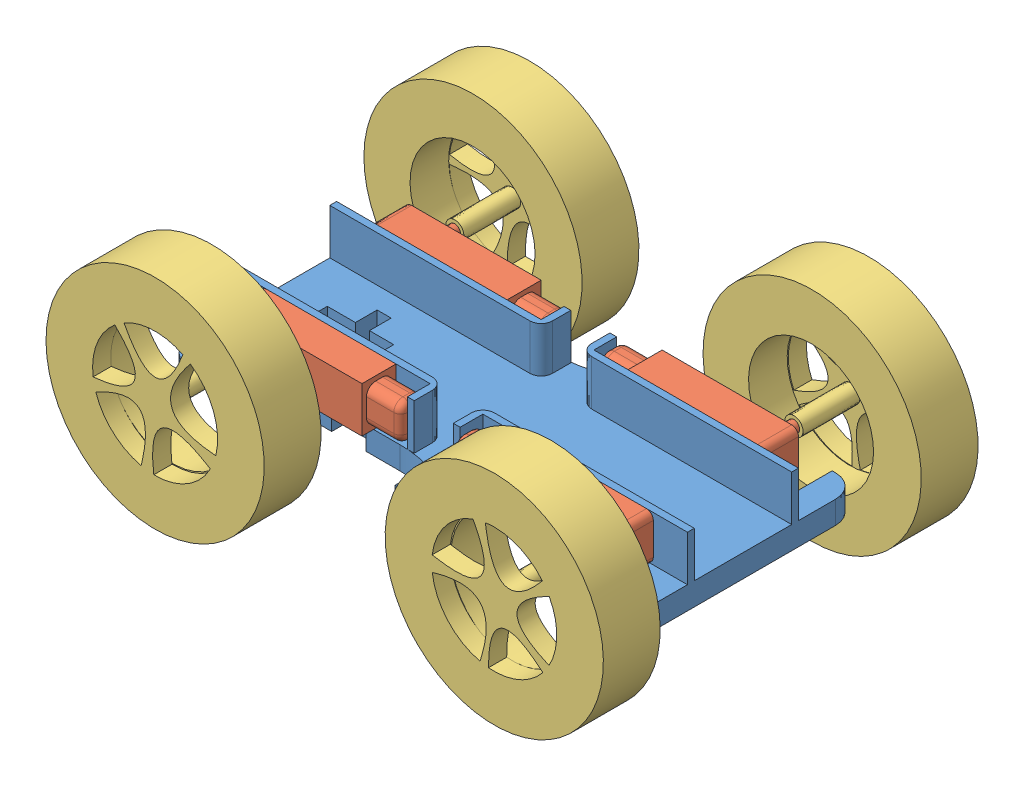
SolidWorks assembly faiyaz, configuration Default. Lengths in mm.
Overall size (284.29 135.72 164.85).
9 component instances, 3 part files, 20 mates.
Components (placement in the parent):
- part 1 car-1: part 1 car [Default] at (131.3198 111.3813 109.2506) size (203.2 30 101.6)
- part2-1: part2 [Default] at (93.8448 141.3813 141.6448) x (1 0 0) z (0 -1 0) size (75 35 20)
- Part3-1: Part3 [Default] at (58.7045 176.9617 166.6749) x (-0.356977 0.934113 0) z (0.934113 0.356977 0) size (96 33 96)
- part2-2: part2 [Default] at (93.8448 121.3813 76.8563) x (1 0 0) z (0 1 0) size (75 35 20)
- Part3-2: Part3 [Default] at (17.0296 153.8801 51.8262) x (-0.602444 0.798162 0) z (-0.798162 -0.602444 0) size (96 33 96)
- part2-3: part2 [Default] at (168.7948 121.3813 141.6448) x (-1 0 0) z (0 1 0) size (75 35 20)
- Part3-3: Part3 [Default] at (220.4705 88.1403 166.6749) x (0.669207 -0.743076 0) z (-0.743076 -0.669207 0) size (96 33 96)
- part2-4: part2 [Default] at (168.7948 141.3813 76.8563) x (-1 0 0) z (0 -1 0) size (75 35 20)
- Part3-4: Part3 [Default] at (188.0999 89.3819 51.8262) x (-0.724157 -0.689635 0) z (0.689635 -0.724157 0) size (96 33 96)
Mates (geometry in assembly coordinates):
- Coincident1: coincident anti-aligned: plane of part 1 car-1 through (131.3198 121.3813 109.2506) normal (0 1 0); plane of part2-1 through (93.8448 121.3813 141.6448) normal (0 -1 0)
- Coincident2: coincident anti-aligned: plane of part 1 car-1 through (29.7198 141.3813 133.6749) normal (0 0 1); plane of part2-1 through (104.7198 121.3813 133.6749) normal (0 0 -1)
- Coincident3: coincident: plane of part 1 car-1 through (119.7198 141.3813 133.6749) normal (-1 0 0); line of part2-1 through (119.7198 127.3813 138.6749) axis (0 1 0)
- Concentric1: concentric aligned: cylinder of part2-1 through (56.7198 131.3813 168.6749) axis (0 0 -1) radius 2.5098; circle of Part3-1
- Coincident10: coincident anti-aligned: plane of part 1 car-1 through (131.3198 121.3813 109.2506) normal (0 1 0); plane of part2-2 through (93.8448 121.3813 76.8563) normal (0 -1 0)
- Coincident11: coincident anti-aligned: plane of part 1 car-1 through (119.7198 141.3813 84.8262) normal (-1 0 0); plane of part2-2 through (119.7198 121.3813 76.8563) normal (1 0 0)
- Coincident12: coincident anti-aligned: plane of part 1 car-1 through (29.7198 141.3813 84.8262) normal (0 0 -1); plane of part2-2 through (104.7198 141.3813 84.8262) normal (0 0 1)
- Concentric2: concentric aligned: axis of part2-2 through (56.7198 131.3813 49.8262) axis (0 0 1); cylinder of Part3-2 through (56.7198 131.3813 49.8262) axis (0 0 1) radius 2.5
- Coincident14: coincident anti-aligned: plane of part 1 car-1 through (131.3198 121.3813 109.2506) normal (0 1 0); plane of part2-3 through (168.7948 121.3813 141.6448) normal (0 -1 0)
- Coincident16: coincident anti-aligned: plane of part 1 car-1 through (142.9198 141.3813 133.6749) normal (1 0 0); plane of part2-3 through (142.9198 121.3813 141.6448) normal (-1 0 0)
- Coincident17: coincident anti-aligned: plane of part 1 car-1 through (232.9198 141.3813 133.6749) normal (0 0 1); plane of part2-3 through (157.9198 141.3813 133.6749) normal (0 0 -1)
- Concentric3: concentric aligned: cylinder of part2-3 through (205.9198 131.3813 168.6749) axis (0 0 -1) radius 2.5098; cylinder of Part3-3 through (205.9198 131.3813 168.6749) axis (0 0 -1) radius 2.5
- Coincident18: coincident anti-aligned: plane of part 1 car-1 through (131.3198 121.3813 109.2506) normal (0 1 0); plane of part2-4 through (168.7948 121.3813 76.8563) normal (0 -1 0)
- Coincident19: coincident anti-aligned: plane of part 1 car-1 through (142.9198 141.3813 84.8262) normal (1 0 0); plane of part2-4 through (142.9198 141.3813 76.8563) normal (-1 0 0)
- Coincident20: coincident anti-aligned: plane of part 1 car-1 through (232.9198 141.3813 84.8262) normal (0 0 -1); plane of part2-4 through (157.9198 121.3813 84.8262) normal (0 0 1)
- Concentric4: concentric aligned: cylinder of part2-4 through (205.9198 131.3813 49.8262) axis (0 0 1) radius 2.5098; cylinder of Part3-4 through (205.9198 131.3813 49.8262) axis (0 0 1) radius 2.5
- Coincident21: coincident anti-aligned: plane of part2-4 through (168.7948 141.3813 49.8262) normal (0 0 -1); plane of Part3-4 through (205.9198 131.3813 49.8262) normal (0 0 1)
- Coincident22: coincident anti-aligned: plane of part2-2 through (93.8448 121.3813 49.8262) normal (0 0 -1); plane of Part3-2 through (56.7198 131.3813 49.8262) normal (0 0 1)
- Coincident23: coincident anti-aligned: plane of part2-3 through (168.7948 121.3813 168.6749) normal (0 0 1); plane of Part3-3 through (205.9198 131.3813 168.6749) normal (0 0 -1)
- Coincident24: coincident anti-aligned: plane of part2-1 through (93.8448 141.3813 168.6749) normal (0 0 1); circle of Part3-1
